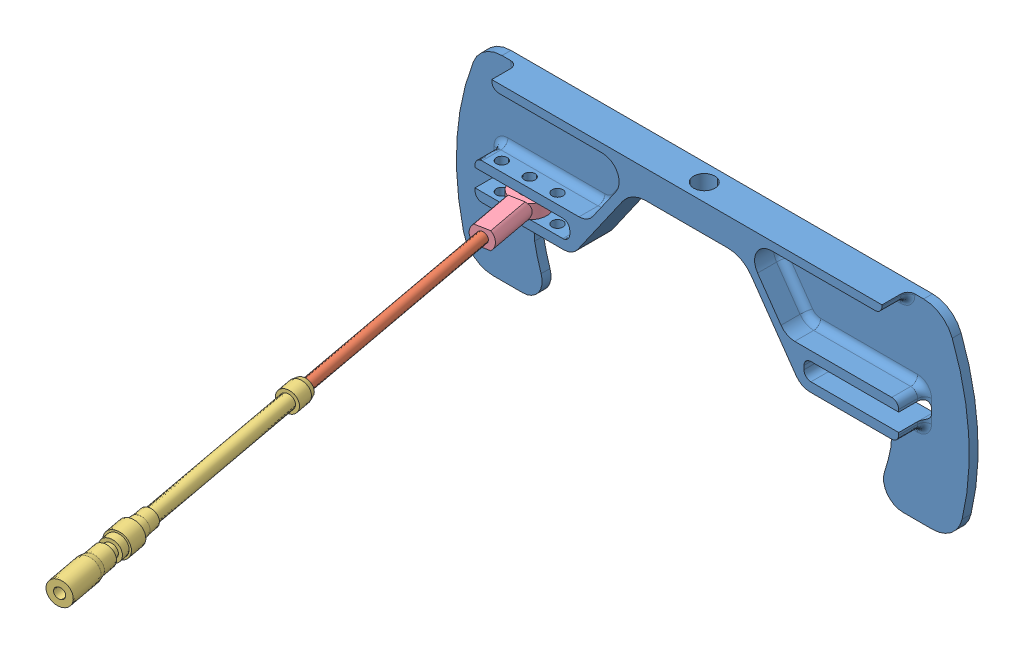
SolidWorks assembly Shifter Assem, configuration Default. Lengths in mm.
Overall size (233.68 88.9 275.83).
4 component instances, 4 part files, 6 mates.
Components (placement in the parent):
- Shifter_2012_v2-1: Shifter_2012_v2 [Default] at (-85.9037 17.6884 21.0614) size (233.68 88.9 15.88)
- Push Pull Cable End-1: Push Pull Cable End [Default] at (-159.488 25.9942 46.3975) x (0.961029 -0.210559 -0.17913) z (-0.183238 0 -0.983069) size (4.76 4.76 127)
- Push Pull cable housing-1: Push Pull cable housing [Default] at (-138.5438 25.9942 158.7622) x (-0.335337 -0.940022 0.062505) z (-0.183238 0 -0.983069) size (11.25 11.25 139.17)
- Rod_end_MW3-1: Rod_end_MW3 [Default] at (-162.1037 25.9942 32.3644) x (0.183238 0 0.983069) z (-0.983069 0 0.183238) size (34.91 7.92 15.88)
Mates (geometry in assembly coordinates):
- Concentric1: concentric anti-aligned: cylinder of Push Pull Cable End-1 through (-136.2167 25.9942 171.2472) axis (-0.183238 0 -0.983069) radius 2.3813; cylinder of Rod_end_MW3-1 through (-157.1608 25.9942 58.8825) axis (0.183238 0 0.983069) radius 2.0193
- Distance1: distance = 12.7 mm anti-aligned: plane of Push Pull Cable End-1 through (-159.488 25.9942 46.3975) normal (-0.183238 0 -0.983069); plane of Rod_end_MW3-1 through (-157.1608 25.9942 58.8825) normal (0.183238 0 0.983069)
- Concentric2: concentric aligned: cylinder of Push Pull Cable End-1 through (-136.2167 25.9942 171.2472) axis (-0.183238 0 -0.983069) radius 2.3813; cylinder of Push Pull cable housing-1 through (-122.3935 25.9942 245.4079) axis (-0.183238 0 -0.983069) radius 3.175
- Distance2: distance = 12.7 mm anti-aligned: plane of Push Pull Cable End-1 through (-136.2167 25.9942 171.2472) normal (0.183238 0 0.983069); plane of Push Pull cable housing-1 through (-138.5438 25.9942 158.7622) normal (-0.183238 0 -0.983069)
- Concentric3: concentric anti-aligned: cylinder of Shifter_2012_v2-1 through (-162.1037 41.2389 32.3644) axis (0 -1 0) radius 2.4892; cylinder of Rod_end_MW3-1 through (-162.1037 22.0318 32.3644) axis (0 1 0) radius 2.413
- Coincident3: coincident anti-aligned: plane of Shifter_2012_v2-1 through (-185.5987 29.9566 36.9364) normal (0 -1 0); plane of Rod_end_MW3-1 through (-162.1037 29.9566 32.3644) normal (0 1 0)
